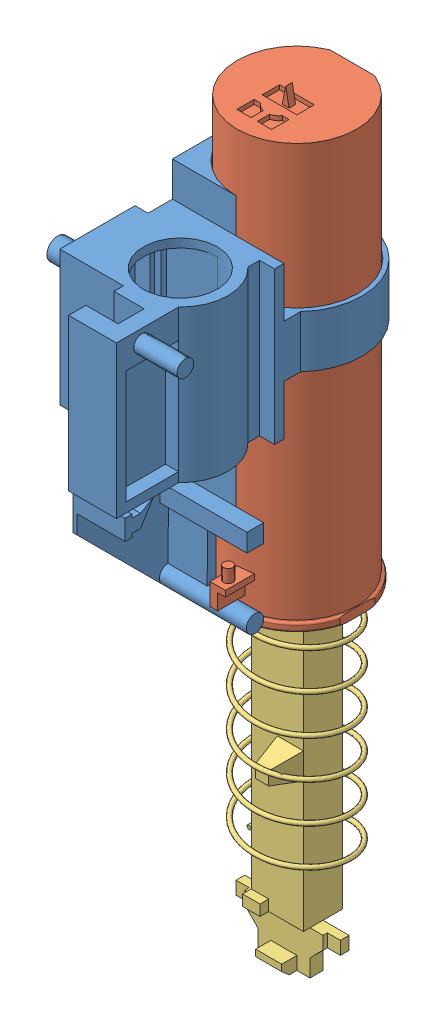
SolidWorks assembly carrier assy, configuration Default. Lengths in mm.
Overall size (39.22 174.51 65.1).
3 component instances, 3 part files, 5 mates.
Components (placement in the parent):
- Carrier-1: Carrier [Default] at (22.0915 43.5029 51.6249) size (39.22 83.08 65.1)
- Nerf cylinder-1: Nerf cylinder [Default] at (22.0915 2.6203 51.6249) x (0 0 -1) z (0 1 0) size (34.5 28.93 100.29)
- Piston-2: Piston [Default] at (22.0915 23.114 51.6249) x (1 0 0) z (0 -1 0) size (25 25 95)
Mates (geometry in assembly coordinates):
- Concentric2: concentric aligned: cylinder of Carrier-1 through (22.0915 78.5029 51.6249) axis (0 -1 0) radius 14; cylinder of Nerf cylinder-1 through (22.0915 99.6203 51.6249) axis (0 -1 0) radius 13.75
- Parallel1: parallel anti-aligned: plane of Carrier-1 through (17.4374 43.5029 51.6249) normal (1 0 0); plane of Nerf cylinder-1 through (22.0915 7.6203 71.6249) normal (-1 0 0)
- Concentric3: concentric anti-aligned: cylinder of Nerf cylinder-1 through (22.0915 80.6203 51.6249) axis (0 -1 0) radius 12; cylinder of Piston-2 through (22.0915 19.114 51.6249) axis (0 1 0) radius 12.5
- Lock1: lock: unknown of Carrier-1; unknown of Nerf cylinder-1
- Parallel2: parallel aligned: plane of Carrier-1 through (28.4374 43.5029 69.4634) normal (0 0 1); plane of Piston-2 through (28.0915 -61.886 56.1249) normal (0 0 1)
